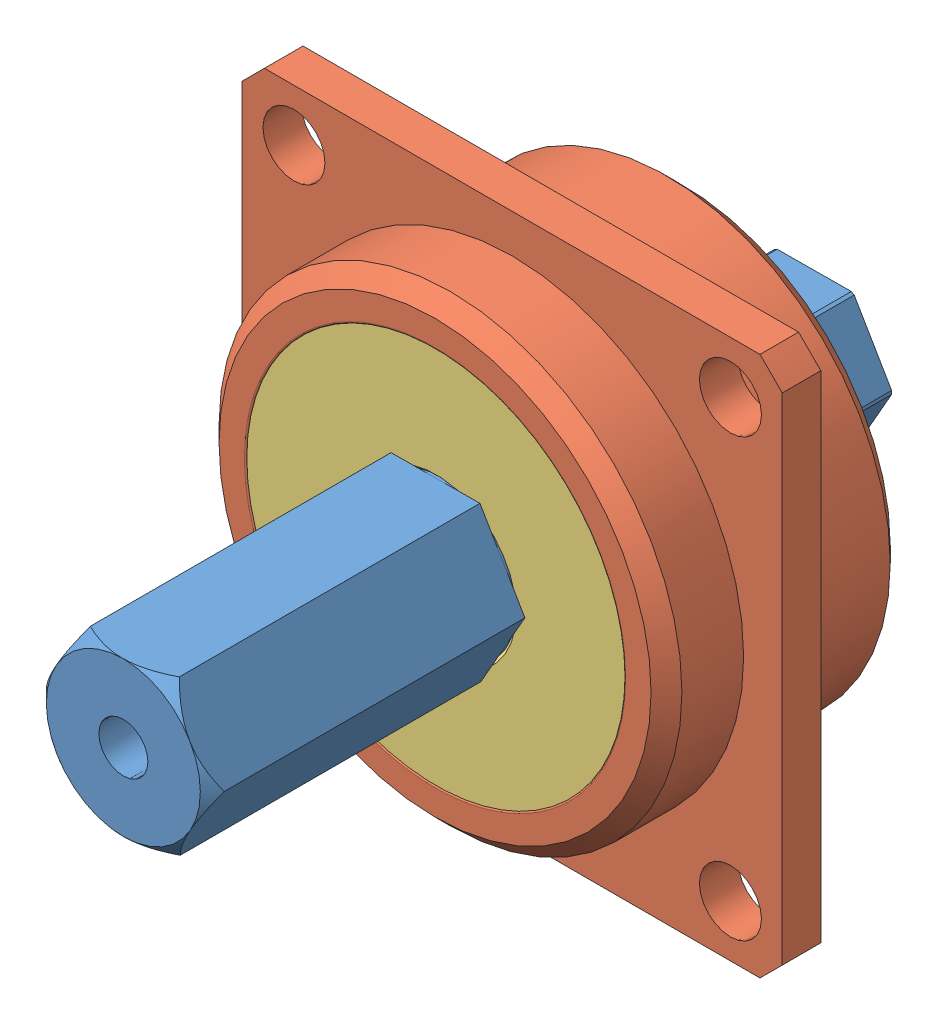
SolidWorks assembly am-XXXX - 57 Sport 500 Hex Output Plug, configuration Default. Lengths in mm.
Overall size (44.45 44.45 56.9).
5 component instances, 4 part files, 0 mates.
Components (placement in the parent):
- am-XXXX - 57 Sport 500 Hex Shaft-1: am-XXXX - 57 Sport 500 Hex Shaft [Default] at (0 0 6.2738) x (0.999982 0.006056 0) z (0 0 1) size (16.1 12.67 56.9)
- Output Block-1: Output Block [Default] at origin size (44.45 44.45 20.32)
- FR8ZZ Bearing-1: FR8ZZ Bearing [Default] at (8.9053 -5.9773 -13.8938) x (0.999973 0.007281 0) z (0 0 1) size (31.75 31.75 7.95)
- FR8ZZ Bearing-2: FR8ZZ Bearing [Default] at (5.8713 8.9755 6.2738) x (0.923728 0.383049 0) z (0 0 -1) size (31.75 31.75 7.95)
- retaining Ring 0500 - Mcm 98410A122_98410A122-1: retaining Ring 0500 - Mcm 98410A122_98410A122 [Default] at (0 0 -14.3891) x (0 0 1) z (-0.999848 0.017452 0) size (0.89 16.1 14.34)
